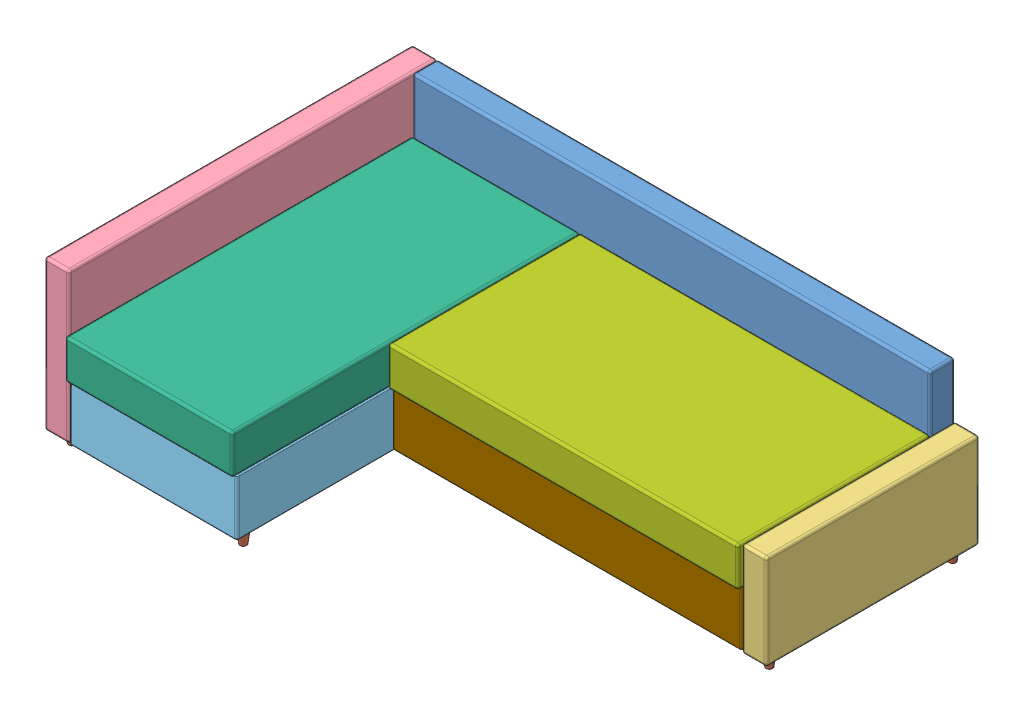
SolidWorks assembly FRIHETEN, configuration Eingeklappt. Lengths in mm.
Overall size (2304.2 662.59 1514.2).
34 component instances, 13 part files, 24 mates.
Components (placement in the parent):
- Rueckwand-1: Rueckwand [Standard] at (-100 0 -3822.8871) size (2104.2 660.82 108.39)
  - Rueckwand-1: Rueckwand [Standard] at (-1050 -220 920.2012) x (-1 0 0) z (0 1 0) size (2104.2 108.39 608.28)
  - Standfuss-1: Standfuss [Standard] at (-1060.9826 -218.2982 927.5163) x (-1 0 0) z (0 0.999999 0.001172) size (43.37 42.87 53.74)
- Seitenwand-Kurz-1: Seitenwand-Kurz [Standard] at (0 -223.006 -629.3385) size (104.2 437.81 867.54)
  - Seitenwand-Kurz-1: Seitenwand-Kurz [Standard] at (-1150 3.006 -1510) x (-1 0 0) z (0 1 0) size (104.2 867.54 385.27)
  - Standfuss-1: Standfuss [Standard] at (-60.9826 4.7078 -1512.6869) x (-1 0 0) z (0 0.999999 0.001172) size (43.37 42.87 53.74)
  - Standfuss-2: Standfuss [Standard] at (-60.9826 4.7078 -2256.0144) x (-1 0 0) z (0 0.999999 0.001172) size (43.37 42.87 53.74)
- Seitenwand-Lang-1: Seitenwand-Lang [Standard] at (-2200 0 0) size (104.2 660.82 1496.88)
  - Seitenwand-Lang-1: Seitenwand-Lang [Standard] at (1050 -220 -1510) x (-1 0 0) z (0 1 0) size (104.2 1496.88 608.31)
  - Standfuss-1: Standfuss [Standard] at (-60.9826 -218.2982 -1512.6869) x (-1 0 0) z (0 0.999999 0.001172) size (43.37 42.87 53.74)
  - Standfuss-2: Standfuss [Standard] at (-60.9826 -218.2982 -2885.3529) x (-1 0 0) z (0 0.999999 0.001172) size (43.37 42.87 53.74)
- Aufklappbox-1: Aufklappbox [Standard] at (-1520 -220 17.3141) size (680.19 440.78 1410.02)
  - Aufbewahrungsbox-1: Aufbewahrungsbox [Standard] at (370 0 -1427.3141) x (-1 0 0) z (0 1 0) size (680.04 1392.73 228.2)
  - Aufbewahrungsmatratze-1: Aufbewahrungsmatratze [Standard] at (370 0 -1410) x (-1 0 0) z (0 1 0) size (680 1410 160)
  - Standfuss-1: Standfuss [Standard] at (-1196.5877 1.7018 -1670.6769) x (-0.601985 0 0.798507) z (0.000936 0.999999 0.000706) size (43.37 42.87 53.74)
  - Standfuss-2: Standfuss [Standard] at (1284.7339 1.7018 -690.2598) x (-0.418517 0 -0.908209) z (-0.001065 0.999999 0.000491) size (43.37 42.87 53.74)
- Matratze-1: Matratze [Standard] at (-470 -220 17.3141) x (1 0 0) z (0 1 0) size (1420 780 160)
- Box-1: Box [Standard] at (-1520 -608.1981 -629.3385) size (1422.41 290.86 765.47)
  - Box-Boden-1: Box-Boden [Standard] at (1050 396.1981 646.6526) x (1 0 0) z (0 1 0) size (1410 741.08 8)
  - Box-Front-1: Box-Front [Standard] at (1050 396.1981 646.6526) x (1 0 0) z (0 1 0) size (1420.62 20.02 228.82)
  - Box-Rahmen-1: Box-Rahmen [Standard] at (1050 396.1981 646.6526) x (1 0 0) z (0 1 0) size (1422.41 745.45 228.79)
  - Rolle-1: Rolle [Standard] at (83.2536 0 -67.2675) size (28.61 54.54 53.59)
    - Rolle-1: Rolle [Standard] at (1010.388 1040.9998 -976.2734) x (1 0 0) z (0 -0.414368 -0.91011) size (23.76 40.47 40.46)
    - Rollenhalter-1: Rollenhalter [Standard] at (1010.388 396.1981 1340.927) x (1 0 0) z (0 1 0) size (28.61 51.43 30.62)
  - Rolle-2: Rolle [Standard] at (1365 0 -67.2675) size (28.61 54.54 53.59)
    - Rolle-1: Rolle [Standard] at (1010.388 1040.9998 -976.2734) x (1 0 0) z (0 -0.414368 -0.91011) size (23.76 40.47 40.46)
    - Rollenhalter-1: Rollenhalter [Standard] at (1010.388 396.1981 1340.927) x (1 0 0) z (0 1 0) size (28.61 51.43 30.62)
  - Rolle-3: Rolle [Standard] at (1365 0 -657.2782) size (28.61 54.54 53.59)
    - Rolle-1: Rolle [Standard] at (1010.388 1040.9998 -976.2734) x (1 0 0) z (0 -0.414368 -0.91011) size (23.76 40.47 40.46)
    - Rollenhalter-1: Rollenhalter [Standard] at (1010.388 396.1981 1340.927) x (1 0 0) z (0 1 0) size (28.61 51.43 30.62)
  - Rolle-4: Rolle [Standard] at (83.2536 0 -657.2782) size (28.61 54.54 53.59)
    - Rolle-1: Rolle [Standard] at (1010.388 1040.9998 -976.2734) x (1 0 0) z (0 -0.414368 -0.91011) size (23.76 40.47 40.46)
    - Rollenhalter-1: Rollenhalter [Standard] at (1010.388 396.1981 1340.927) x (1 0 0) z (0 1 0) size (28.61 51.43 30.62)
- Ausklappmatratze-1: Ausklappmatratze [Standard] at (-470 -280.1981 17.3141) x (1 0 0) z (0 1 0) size (1380.04 635.87 160.08)
Mates (geometry in assembly coordinates):
- Deckungsgleich2: coincident anti-aligned: plane of Rueckwand-1/Rueckwand-1 through (-2200 0 -1392.6859) normal (-1 0 0); plane of Seitenwand-Lang-1/Seitenwand-Lang-1 through (-2200 0 -1492.6859) normal (1 0 0)
- Deckungsgleich3: coincident aligned: plane of Rueckwand-1/Rueckwand-1 through (-2200 0 -1492.6859) normal (0 0 -1); plane of Seitenwand-Lang-1/Seitenwand-Lang-1 through (-2300 0 -1492.6859) normal (0 0 -1)
- Deckungsgleich4: coincident aligned: plane of Rueckwand-1/Rueckwand-1 through (-2200 -608.1981 -1492.6859) normal (0 -1 0); plane of Seitenwand-Lang-1/Seitenwand-Lang-1 through (-2300 -608.1981 -1492.6859) normal (0 -1 0)
- Deckungsgleich5: coincident aligned: plane of Rueckwand-1/Rueckwand-1 through (-2200 -608.1981 -1492.6859) normal (0 -1 0); plane of Seitenwand-Kurz-1/Seitenwand-Kurz-1 through (-100 -608.1981 -1492.6859) normal (0 -1 0)
- Deckungsgleich6: coincident anti-aligned: plane of Rueckwand-1/Rueckwand-1 through (-100 0 -1492.6859) normal (1 0 0); plane of Seitenwand-Kurz-1/Seitenwand-Kurz-1 through (-100 -223.006 -629.3385) normal (-1 0 0)
- Deckungsgleich7: coincident aligned: plane of Rueckwand-1/Rueckwand-1 through (-2200 0 -1492.6859) normal (0 0 -1); plane of Seitenwand-Kurz-1/Seitenwand-Kurz-1 through (-100 -223.006 -1492.6859) normal (0 0 -1)
- Deckungsgleich8: coincident anti-aligned: plane of Rueckwand-1/Rueckwand-1 through (-100 0 -1392.6859) normal (0 0 1); plane of Aufklappbox-1/Aufbewahrungsbox-1 through (-2200 -380 -1392.6859) normal (0 0 -1)
- Deckungsgleich9: coincident anti-aligned: plane of Seitenwand-Lang-1/Seitenwand-Lang-1 through (-2200 0 -1492.6859) normal (1 0 0); plane of Aufklappbox-1/Aufbewahrungsbox-1 through (-2200 -380 0) normal (-1 0 0)
- Deckungsgleich10: coincident aligned: plane of Rueckwand-1/Rueckwand-1 through (-2200 -608.1981 -1492.6859) normal (0 -1 0); plane of Aufklappbox-1/Aufbewahrungsbox-1 through (-2200 -608.1981 -1392.6859) normal (0 -1 0)
- Deckungsgleich11: coincident anti-aligned: plane of Rueckwand-1/Rueckwand-1 through (-100 0 -1392.6859) normal (0 0 1); plane of Matratze-1 through (-1520 -220 -1392.6859) normal (0 0 -1)
- Deckungsgleich12: coincident aligned: plane of Aufklappbox-1/Aufbewahrungsmatratze-1 through (-2200 -220 -1392.6859) normal (0 1 0); plane of Matratze-1 through (-100 -220 -612.6859) normal (0 1 0)
- Deckungsgleich13: coincident anti-aligned: plane of Seitenwand-Kurz-1/Seitenwand-Kurz-1 through (-100 -223.006 -629.3385) normal (-1 0 0); plane of Matratze-1 through (-100 -220 -1392.6859) normal (1 0 0)
- Deckungsgleich14: coincident anti-aligned: plane of Box-1/Box-Boden-1 through (-105 -600.1981 -646.606) normal (0 1 0); plane of Ausklappmatratze-1 through (-120 -600.1981 -649.3385) normal (0 -1 0)
- Deckungsgleich15: coincident anti-aligned: plane of Box-1/Box-Rahmen-1 through (-120 -372 -1392.6859) normal (-1 0 0); plane of Ausklappmatratze-1 through (-120 -440.1981 -1277.9117) normal (1 0 0)
- Deckungsgleich16: coincident anti-aligned: plane of Box-1/Box-Front-1 through (-100 -600.1981 -649.3385) normal (0 0 -1); plane of Ausklappmatratze-1 through (-120 -440.1981 -649.3385) normal (0 0 1)
- Deckungsgleich17: coincident anti-aligned: plane of Seitenwand-Kurz-1/Seitenwand-Kurz-1 through (-100 -223.006 -629.3385) normal (-1 0 0); plane of Box-1/Box-Rahmen-1 through (-100 -372 -1392.6859) normal (1 0 0)
- Deckungsgleich18: coincident anti-aligned: plane of Rueckwand-1/Rueckwand-1 through (-100 0 -1392.6859) normal (0 0 1); plane of Box-1/Box-Rahmen-1 through (-1520 -372 -1392.6859) normal (0 0 -1)
- Deckungsgleich19: coincident aligned: plane of Aufklappbox-1/Aufbewahrungsbox-1 through (-2200 -608.1981 -1392.6859) normal (0 -1 0); plane of Box-1/Box-Boden-1 through (-105 -608.1981 -646.606) normal (0 -1 0)
- Deckungsgleich20: coincident aligned: plane of Seitenwand-Lang-1/Seitenwand-Lang-1 through (-2300 0 -1492.6859) normal (0 1 0); plane of assembly through (0 0 0) normal (0 1 0)
- Deckungsgleich21: coincident aligned: plane of Seitenwand-Lang-1/Seitenwand-Lang-1 through (-2200 0 0) normal (0 0 1); plane of assembly through (0 0 0) normal (0 0 1)
- Deckungsgleich22: coincident aligned: plane of Seitenwand-Kurz-1/Seitenwand-Kurz-1 through (0 -223.006 -1492.6859) normal (1 0 0); plane of assembly through (0 0 0) normal (1 0 0)
- Deckungsgleich23: coincident aligned: plane of Aufklappbox-1/Aufbewahrungsbox-1 through (-1520 -380 0) normal (0 0 1); plane of Box-1/Box-Front-1 through (-100 -372 0) normal (0 0 1)
- Deckungsgleich24: coincident: plane of Aufklappbox-1/Aufbewahrungsmatratze-1 through (-1520 -220 17.3141) normal (0 0 1); plane of Ausklappmatratze-1 through (-120 -196.6071 17.3141) normal (0 0 1)
- Deckungsgleich25: coincident aligned: plane of Aufklappbox-1/Aufbewahrungsmatratze-1 through (-2200 -220 -1392.6859) normal (0 1 0); plane of Ausklappmatratze-1 through (-120 -220 17.3141) normal (0 1 0)
